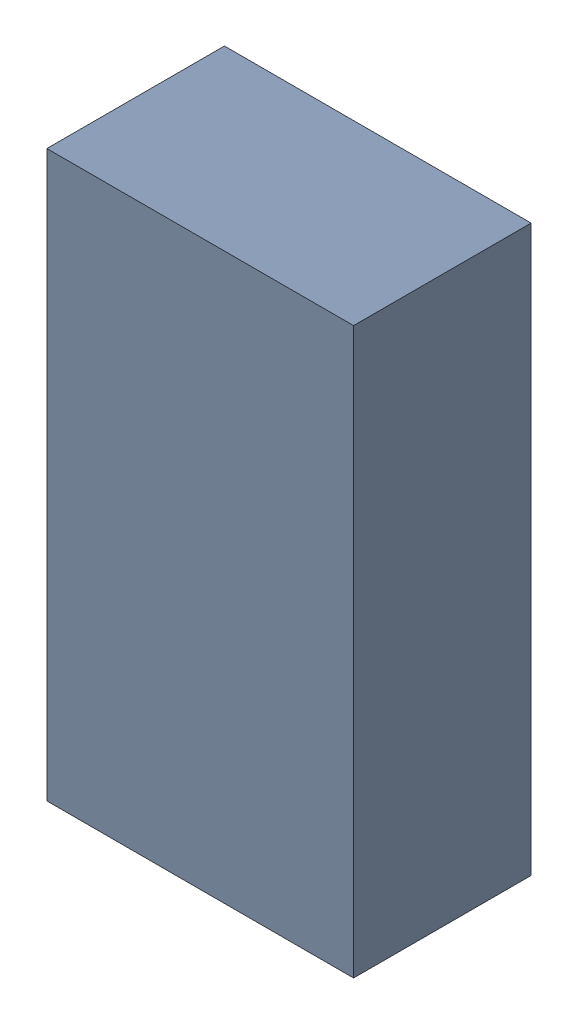
SolidWorks assembly L3_TDA1, configuration Standard. Lengths in mm.
Overall size (0.95 1.75 0.55).
2 component instances, 1 part files, 0 mates.
Components (placement in the parent):
- 885542784-1: 885542784 [Standard] at (3.15 58.43 0) size (0.95 1.75 0.55)
  - Extruded_22-1: Extruded_22 [Standard] at origin size (0.95 1.75 0.55)
